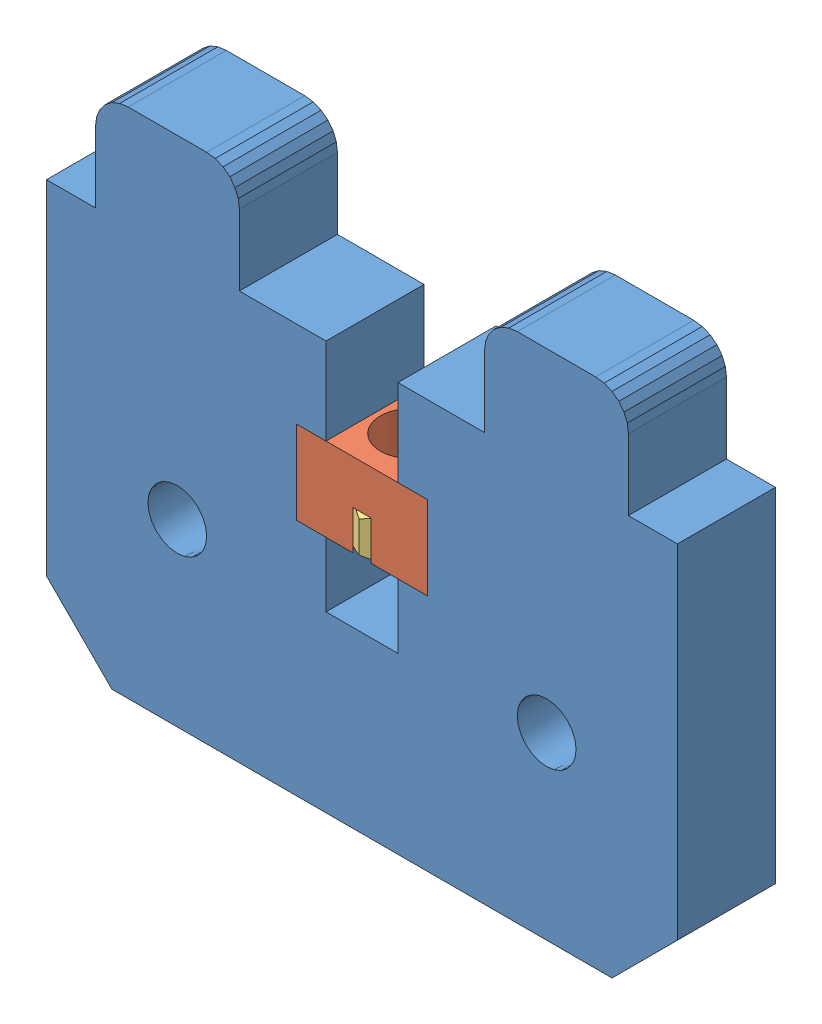
SolidWorks assembly Assembly Y-Belt Holder, configuration Valor predeterminado. Lengths in mm.
Overall size (38.6 31.35 7.94).
4 component instances, 3 part files, 3 mates.
Components (placement in the parent):
- Y-Belt Holder-1: Y-Belt Holder [Valor predeterminado] at (-46.3144 -22.3724 35.6) size (38.6 31.35 6)
- Assembly m3-nut-adapter + Nut DIN 934 - M3-1: Assembly m3-nut-adapter + Nut DIN 934 - M3 [Valor predeterminado] at (-1.3588 3.4475 38.6) x (1 0 0) z (0 -1 0) size (8.25 7.94 5.1)
  - m3-nut-adapter-1: m3-nut-adapter [Valor predeterminado] at origin size (8 6 5.1)
  - Nut DIN 934 - M3-1: Nut DIN 934 - M3 [Valor predeterminado] at (0 0 3.9) x (0 0 1) z (-0.866025 -0.5 0) size (2.4 5.5 6.35)
Mates (geometry in assembly coordinates):
- Coincidente1: coincident: plane of assembly; plane of assembly; plane of Y-Belt Holder-1 through (-46.3144 -22.3724 41.6) normal (0 0 1); plane of Assembly m3-nut-adapter + Nut DIN 934 - M3-1/m3-nut-adapter-1 through (-5.3588 -1.6525 41.6) normal (0 0 1)
- Coincidente2: coincident: plane of assembly; plane of assembly; plane of Y-Belt Holder-1 through (2.6412 -1.6525 41.6) normal (-1 0 0); plane of Assembly m3-nut-adapter + Nut DIN 934 - M3-1/m3-nut-adapter-1 through (2.6412 -1.6525 41.6) normal (1 0 0)
- Coincidente3: coincident: plane of assembly; plane of assembly; plane of Y-Belt Holder-1 through (2.6412 3.4475 41.6) normal (0 -1 0); plane of Assembly m3-nut-adapter + Nut DIN 934 - M3-1/m3-nut-adapter-1 through (-1.3588 3.4475 38.6) normal (0 1 0)
